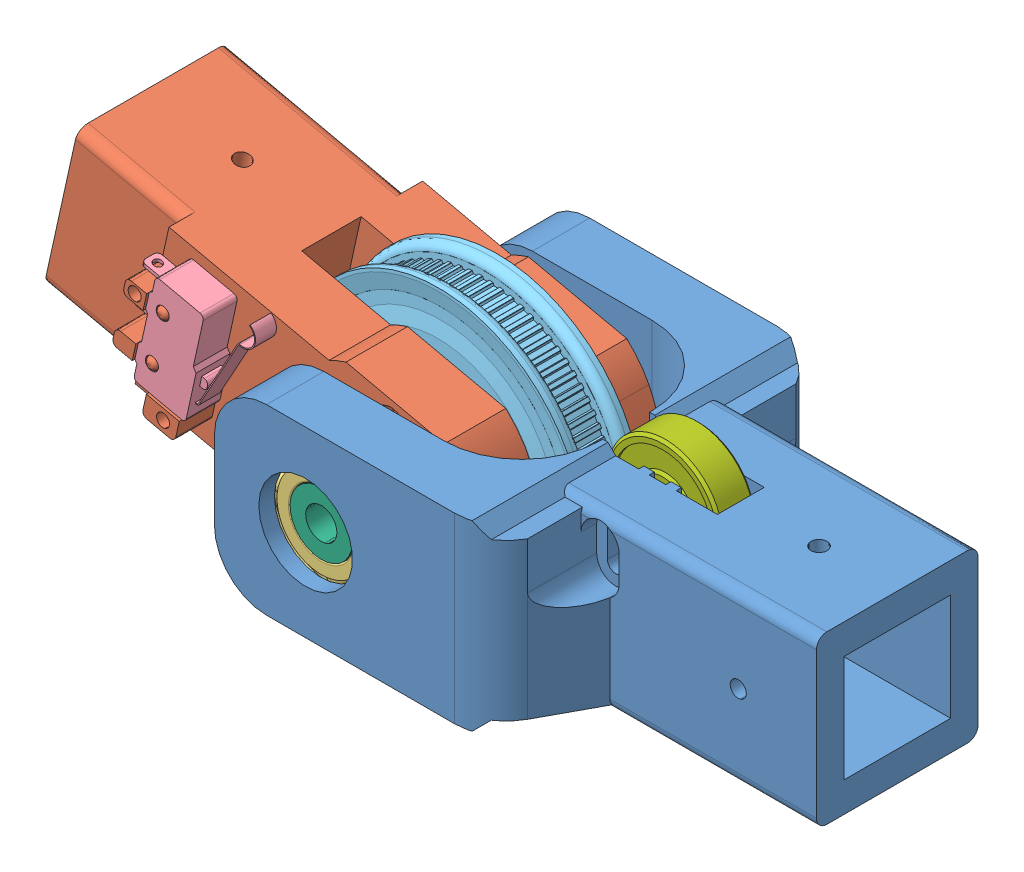
SolidWorks assembly Gomito, configuration Default. Lengths in mm.
Overall size (149.64 66.76 63).
9 component instances, 8 part files, 18 mates.
Components (placement in the parent):
- gomito_j1-1: gomito_j1 [Default] at (-1.2106 28.0316 -14.5) size (100 35 62)
- gomito_j2-1: gomito_j2 [Default] at (-103.5211 38.9277 -14.5) x (-0.976445 0.215764 0) z (0 0 1) size (84.55 34 44.4)
- SKF BALL BEARING 6001 12x28x8-1: SKF BALL BEARING 6001 12x28x8 [Predeterminado] at (-54.2106 28.0316 20) x (0 0 1) z (-1 0 0) size (8 28 28)
- SKF BALL BEARING 6001 12x28x8-2: SKF BALL BEARING 6001 12x28x8 [Predeterminado] at (-54.2106 28.0316 -28) x (0 0 1) z (0.424357 -0.905495 0) size (8 28 28)
- Switch #1405-2: Switch #1405 [По умолчанию] at (-87.1315 38.4809 20.75) x (0 0 -1) z (-0.215764 -0.976445 0) size (6.5 22.26 23.14)
- PULLEY_gt2-1: PULLEY_gt2 [Valor predeterminado] at (-54.2106 28.0316 -3.05) x (0 0 1) z (-0.215764 -0.976445 0) size (11.3 56 56)
- albero-2: albero [Default] at (-54.2106 28.0316 28) x (0.998861 -0.04772 0) z (0.04772 0.998861 0) size (16 60 16)
- Bearig 8x22x7-1: Bearig 8x22x7 [Default] at (-13.2106 39.0316 0) x (0.322486 0.946574 0) z (0 0 1) size (22 22 7)
- boccola_8_3-1: boccola_8_3 [Default] at (-13.2106 39.0316 -3.5) size (8 8 8)
Mates (geometry in assembly coordinates):
- Concentrico1: concentric anti-aligned: cylinder of gomito_j1-1 through (-54.2106 28.0316 -28) axis (0 0 1) radius 14.05; cylinder of SKF BALL BEARING 6001 12x28x8-2 through (-54.2106 28.0316 -28) axis (0 0 -1) radius 14
- Concentrico2: concentric aligned: cylinder of gomito_j1-1 through (-54.2106 28.0316 28) axis (0 0 -1) radius 14.05; cylinder of SKF BALL BEARING 6001 12x28x8-1 through (-54.2106 28.0316 20) axis (0 0 -1) radius 14
- Coincidente1: coincident anti-aligned: plane of gomito_j1-1 through (-54.2106 28.0316 28) normal (0 0 -1); plane of SKF BALL BEARING 6001 12x28x8-1 through (-54.2106 42.0316 28) normal (0 0 1)
- Coincidente2: coincident anti-aligned: plane of gomito_j1-1 through (-54.2106 28.0316 -28) normal (0 0 1); plane of SKF BALL BEARING 6001 12x28x8-2 through (-66.8875 22.0906 -28) normal (0 0 -1)
- Concentrico6: concentric aligned: cylinder of gomito_j2-1 through (-54.2106 28.0316 -17.5) axis (0 0 1) radius 6; cylinder of PULLEY_gt2-1 through (-54.2106 28.0316 -5.7) axis (0 0 1) radius 4
- Larghezza2: width anti-aligned: plane of gomito_j2-1 through (-42.8004 10.1485 -5.7) normal (0 0 1); plane of gomito_j2-1 through (-42.8004 10.1485 5.7) normal (0 0 -1); plane of PULLEY_gt2-1 through (-54.2106 28.0316 -5.6) normal (0 0 -1); plane of PULLEY_gt2-1 through (-54.2106 28.0316 5.6) normal (0 0 1)
- Concentrico8: concentric aligned: cylinder of gomito_j2-1 through (-51.4057 40.7254 -17.5) axis (0 0 1) radius 1.75; cylinder of PULLEY_gt2-1 through (-51.4057 40.7254 -5.7) axis (0 0 1) radius 1.75
- Concentrico9: concentric anti-aligned: cylinder of SKF BALL BEARING 6001 12x28x8-2 through (-54.2106 28.0316 -28) axis (0 0 -1) radius 6; cylinder of PULLEY_gt2-1 through (-54.2106 28.0316 -5.7) axis (0 0 1) radius 4
- Larghezza3: width anti-aligned: plane of SKF BALL BEARING 6001 12x28x8-1 through (-54.2106 36.5316 20) normal (0 0 -1); plane of SKF BALL BEARING 6001 12x28x8-2 through (-61.9073 24.4246 -20) normal (0 0 1); plane of gomito_j2-1 through (-54.2106 28.0316 19.9) normal (0 0 1); plane of gomito_j2-1 through (-54.2106 28.0316 -19.9) normal (0 0 -1)
- Concentrico10: concentric anti-aligned: cylinder of SKF BALL BEARING 6001 12x28x8-2 through (-54.2106 28.0316 -28) axis (0 0 -1) radius 6; cylinder of albero-2 through (-54.2106 28.0316 -28) axis (0 0 1) radius 6
- Coincidente9: coincident anti-aligned: plane of SKF BALL BEARING 6001 12x28x8-2 through (-61.9073 24.4246 -28) normal (0 0 -1); plane of albero-2 through (-54.2106 28.0316 -28) normal (0 0 1)
- Coincidente10: coincident anti-aligned: plane of gomito_j2-1 through (-42.8004 10.1485 17.5) normal (0 0 1); plane of Switch #1405-2 through (-87.1315 38.4809 17.5) normal (0 0 -1)
- Concentrico11: concentric anti-aligned: cylinder of gomito_j2-1 through (-90.7059 34.3549 24.5) axis (0 0 -1) radius 1.2; cylinder of Switch #1405-2 through (-90.7059 34.3549 17.5) axis (0 0 1) radius 1.25
- Concentrico12: concentric anti-aligned: cylinder of gomito_j2-1 through (-88.6346 43.7288 24.5) axis (0 0 -1) radius 1.2; cylinder of Switch #1405-2 through (-88.6346 43.7288 17.5) axis (0 0 1) radius 1.25
- Concentrico13: concentric aligned: cylinder of gomito_j1-1 through (-13.2106 39.0316 31) axis (0 0 -1) radius 1.6; cylinder of Bearig 8x22x7-1 through (-13.2106 39.0316 3.5) axis (0 0 -1) radius 4
- Larghezza4: width anti-aligned: plane of Bearig 8x22x7-1 through (-13.2106 39.0316 -3.5) normal (0 0 -1); plane of gomito_j1-1 through (-13.2106 39.0316 3.5) normal (0 0 1); plane of Bearig 8x22x7-1 through (-1.2106 28.0316 -3.5) normal (0 0 1); plane of gomito_j1-1 through (-1.2106 28.0316 3.5) normal (0 0 -1)
- Coincidente11: coincident aligned: plane of Bearig 8x22x7-1 through (-13.2106 39.0316 -3.5) normal (0 0 -1); plane of boccola_8_3-1 through (-8.8454 51.6748 -3.5) normal (0 0 -1)
- Concentrico14: concentric aligned: cylinder of Bearig 8x22x7-1 through (-13.2106 39.0316 3.5) axis (0 0 -1) radius 4; cylinder of boccola_8_3-1 through (-8.8454 51.6748 4.5) axis (0 0 -1) radius 4
